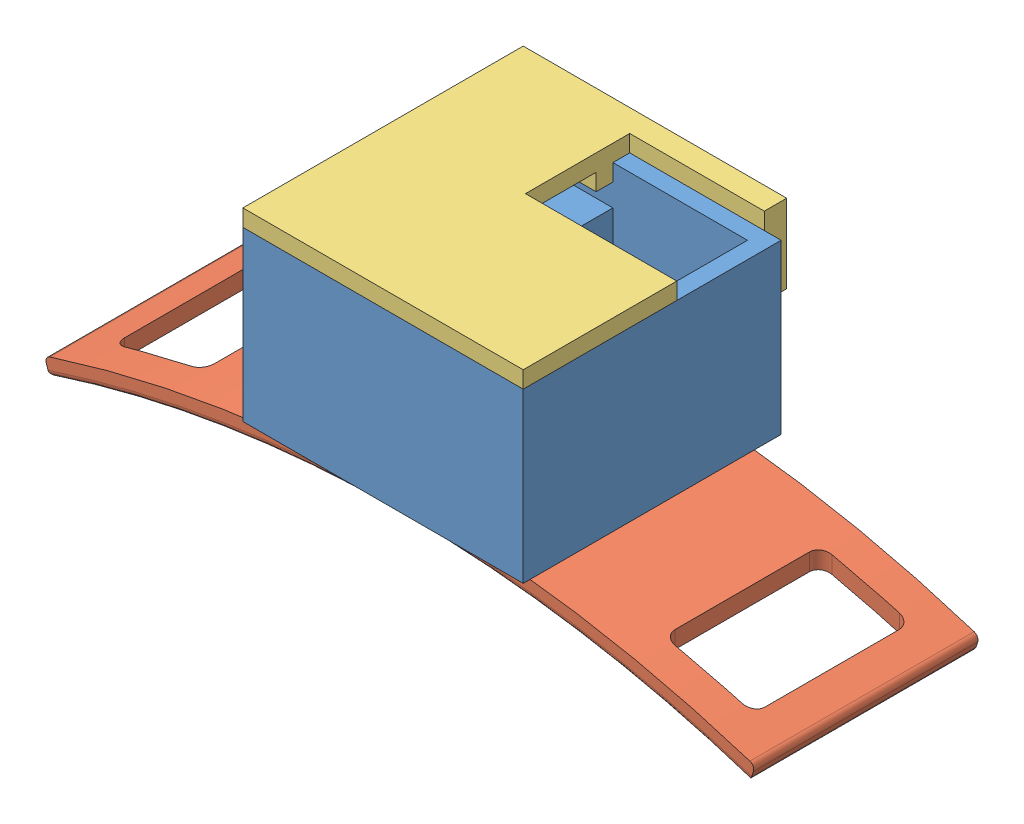
SolidWorks assembly Assem1, configuration Default. Lengths in mm.
Overall size (63.12 23.07 25).
3 component instances, 3 part files, 6 mates.
Components (placement in the parent):
- caja accel-1: caja accel [Default] at origin size (25 15 23)
- base-1: base [Default] at (0 -101.7 -10) size (63.12 6.57 20.09)
- tapa-1: tapa [Default] at (0 16.5 0) x (-1 0 0) z (0 0 1) size (25 7 25)
Mates (geometry in assembly coordinates):
- Coincident1: coincident: plane of assembly; plane of assembly; plane of caja accel-1 through (0 0 0) normal (0 -1 0); plane of base-1 through (-10 0 -30.012) normal (0 1 0)
- Distance1: distance = 1.5 mm: plane of assembly; plane of assembly; plane of base-1 through (0 -101.7 -10) normal (0 0 -1); plane of caja accel-1 through (-12.5 15 -11.5) normal (0 0 -1)
- Distance2: distance = 2.5 mm: plane of assembly; plane of assembly; plane of base-1 through (10 0 -30.012) normal (1 0 0); plane of caja accel-1 through (12.5 15 11.5) normal (1 0 0)
- Coincident5: coincident: plane of assembly; plane of assembly; plane of caja accel-1 through (11 15 11.5) normal (-1 0 0); plane of tapa-1 through (11 13.5 10) normal (1 0 0)
- Coincident6: coincident: plane of assembly; plane of assembly; plane of caja accel-1 through (0 15 0) normal (0 1 0); plane of tapa-1 through (0 15 0) normal (0 -1 0)
- Coincident7: coincident: plane of assembly; plane of assembly; plane of caja accel-1 through (-12.5 15 11.5) normal (0 0 1); plane of tapa-1 through (12.5 15 11.5) normal (0 0 1)
